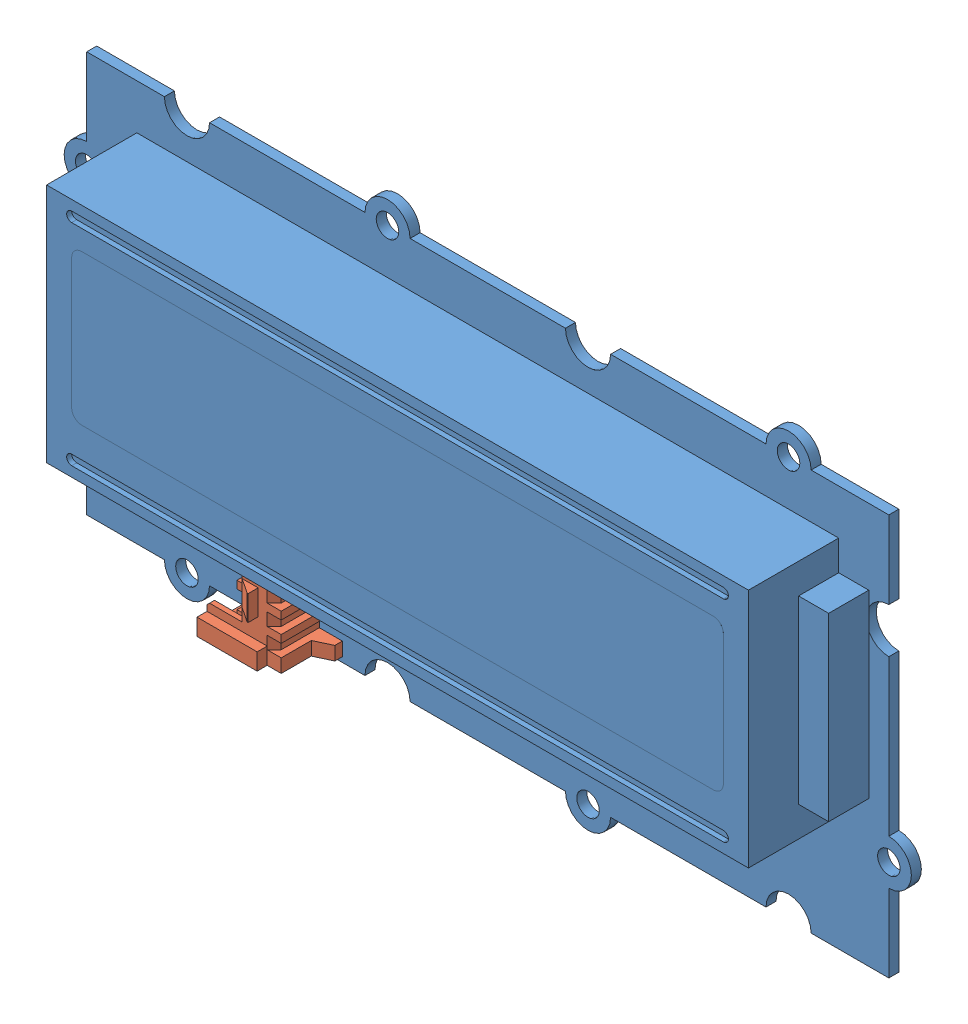
SolidWorks assembly Grove LCD RGB Backlight, configuration Défaut. Lengths in mm.
Overall size (84.5 44.5 10).
2 component instances, 2 part files, 3 mates.
Components (placement in the parent):
- LCD RGB Backlight-1: LCD RGB Backlight [Défaut] at (-6.532 1.7619 75) size (84.5 44.5 10)
- Connecteur BSG-1: Connecteur BSG [Défaut] at (-24.032 -12.7381 76) x (0 -1 0) z (-1 0 0) size (10 5.5 9)
Mates (geometry in assembly coordinates):
- Coïncidente5: coincident anti-aligned: plane of LCD RGB Backlight-1 through (-46.532 11.7619 76) normal (0 0 1); plane of Connecteur BSG-1 through (-30.032 -17.7381 76) normal (0 0 -1)
- Distance3: distance = 0.5 mm aligned: plane of Connecteur BSG-1 through (-30.032 -17.7381 76) normal (0 -1 0); plane of LCD RGB Backlight-1 through (-46.532 -18.2381 76) normal (0 -1 0)
- Distance4: distance = 16.5 mm aligned: plane of Connecteur BSG-1 through (-30.032 -12.7381 76) normal (-1 0 0); plane of LCD RGB Backlight-1 through (-46.532 21.7619 76) normal (-1 0 0)
